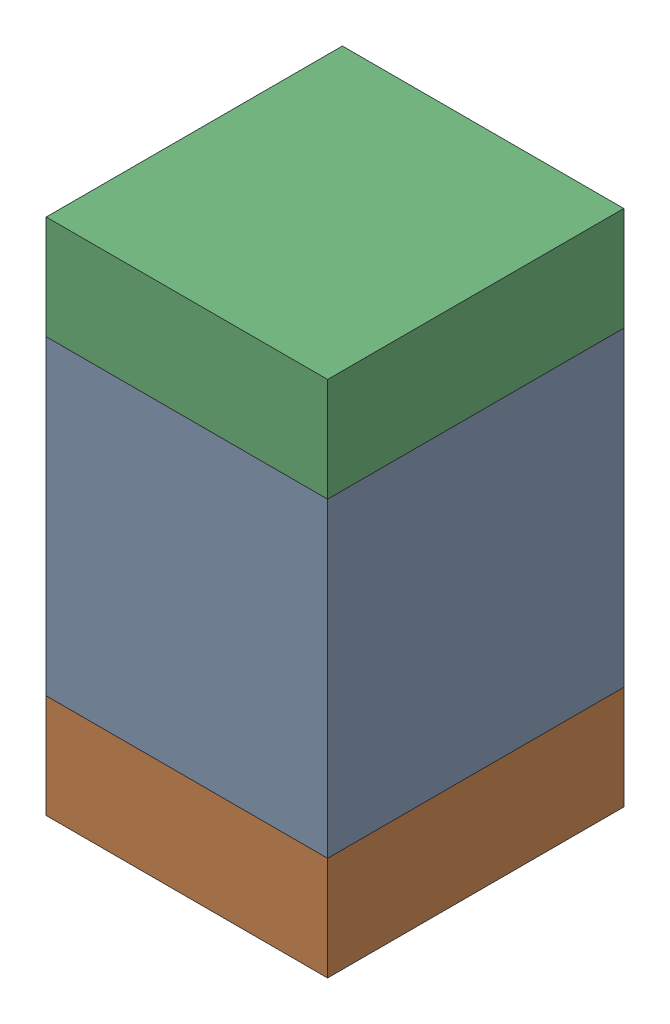
SolidWorks assembly C318_2PCB, configuration Default. Lengths in mm.
Overall size (0.95 1.75 1).
6 component instances, 2 part files, 0 mates.
Components (placement in the parent):
- 761616384-1: 761616384 [Default] at (123.3 94 -2.6638) size (0.95 1.05 1)
  - Extruded_5-1: Extruded_5 [Default] at origin size (0.95 1.05 1)
- 761616520-1: 761616520 [Default] at (123.3 93.3 -2.6638) size (0.95 0.35 1)
  - Extruded_6-1: Extruded_6 [Default] at origin size (0.95 0.35 1)
- 761616520-2: 761616520 [Default] at (123.3 94.7 -2.6638) size (0.95 0.35 1)
  - Extruded_6-1: Extruded_6 [Default] at origin size (0.95 0.35 1)
